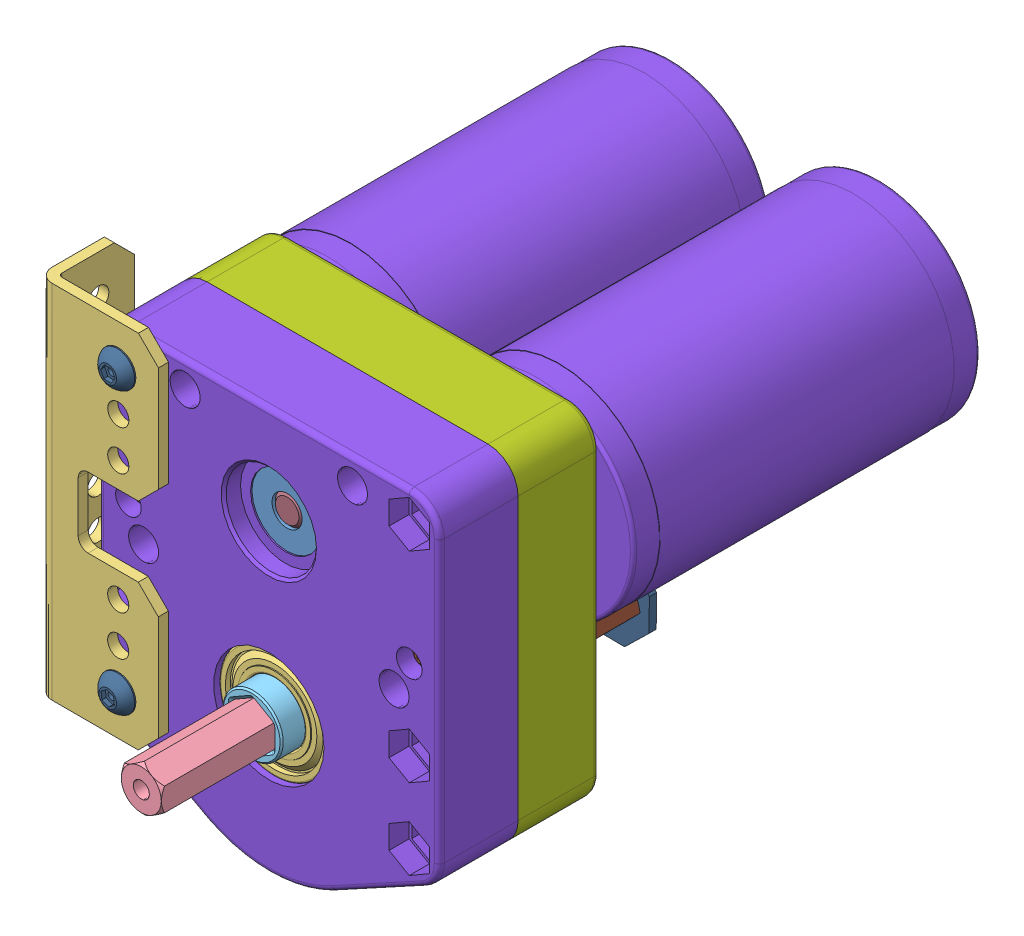
SolidWorks assembly 217-2428 LEFT, configuration Default. Lengths in mm.
Overall size (144.51 134.21 205.51).
82 component instances, 46 part files, 7 mates.
Components (placement in the parent):
- 217-2733-1: 217-2733 [Default] at (0 53.4162 12.0523) x (0 0 1) z (-0.971723 0.236125 0) size (7.11 24.61 24.61)
- 217-2733-2: 217-2733 [Default] at (0 53.4162 -17.6911) x (0 0 -1) z (0.971421 0.237365 0) size (7.11 24.61 24.61)
- 217-2731-1: 217-2731 [Default] at (0 0 -25.6286) x (1 0 0) z (0 -1 0) size (31.12 7.94 31.12)
- 217-2789-1: 217-2789 [Default] at (0 0 17.6784) x (0 0 -1) z (0.906537 -0.422126 0) size (11.1 38.4 38.4)
- 217-2778-001 Rev2_NCQ8A075-050M-1: 217-2778-001 Rev2_NCQ8A075-050M [Default] at (0 0 -79.4639) x (-0.681873 0.731471 0) z (0 0 1) size (31.75 33.34 41.8)
  - 217-2778-NCQ8A075-050M_NCQ8 Tube_075A-1: 217-2778-NCQ8A075-050M_NCQ8 Tube_075A [Default] at origin size (31.75 33.34 26.92)
  - 217-2778-NCQ8A075-050M_NCQ8 Rod_075M-1: 217-2778-NCQ8A075-050M_NCQ8 Rod_075M [Default] at (0 0 -6.927) x (-1 0 0) z (0 0 1) size (18.95 18.95 35.27)
  - 217-2778-NCQ8A075-050M_Snap Ring_075-1: 217-2778-NCQ8A075-050M_Snap Ring_075 [Default] at (0 0 10.362) size (21 20.74 0.97)
- 217-2428-027 Rev1_97414A630-1: 217-2428-027 Rev1_97414A630 [Default] at (0 0 -44.8925) x (0 0 1) z (0.453751 0.891129 0) size (0.64 5.89 7.9)
- 217-2788_57155K375-1: 217-2788_57155K375 [Default] at (0 0 -46.7975) x (0.971787 -0.235861 0) z (0 0 1) size (9.53 9.53 3.17)
- 217-2428-011 Rev2-1: 217-2428-011 Rev2 [Default] at (0 0 -53.992) x (0 -1 0) z (0 0 -1) size (18.03 18.03 17.56)
- 217-2428-012 Rev1-1: 217-2428-012 Rev1 [Default] at (-0.0022 -0.3376 -66.0019) x (0.999912 -0.013293 0) z (0 0 1) size (63.5 25.4 2.29)
- 217-2428-027 Rev1_97414A630-2: 217-2428-027 Rev1_97414A630 [Default] at (0 0 -48.7025) x (0 0 1) z (-0.054891 -0.998492 0) size (0.64 5.89 7.9)
- 217-2428-005 Rev1-1: 217-2428-005 Rev1 [Default] at (25.3955 -0.6753 -44.6659) x (-0.968533 0.248884 0) z (0.248884 0.968533 0) size (7.33 38.98 6.35)
- 217-2428-005 Rev1-2: 217-2428-005 Rev1 [Default] at (-25.4 0 -44.6659) x (0.661665 -0.7498 0) z (-0.7498 -0.661665 0) size (7.33 38.98 6.35)
- SCREW-B-440-0250_91306A311-1: SCREW-B-440-0250_91306A311 [Default] at (3.4925 6.0492 -45.21) x (0.999997 0.002364 0) z (0 0 1) size (5.45 5.47 5.03)
- SCREW-B-440-0250_91306A311-2: SCREW-B-440-0250_91306A311 [Default] at (3.4925 -6.0492 -45.21) x (0.883226 0.468948 0) z (0 0 1) size (5.45 5.47 5.03)
- SCREW-B-440-0250_91306A311-3: SCREW-B-440-0250_91306A311 [Default] at (-6.985 0 -45.21) size (5.45 5.47 5.03)
- SCREW-832-0375-1: SCREW-832-0375 [Default] at (25.3955 -0.6753 -68.2117) x (0 0 1) z (-0.875404 0.483392 0) size (11.73 7.92 7.92)
- SCREW-832-0375-2: SCREW-832-0375 [Default] at (-25.4 0 -68.2117) x (0 0 1) z (-0.875404 0.483392 0) size (11.73 7.92 7.92)
- SCREW-832-0375-3: SCREW-832-0375 [Default] at (25.3955 -0.6753 -20.2311) x (0 0 -1) z (1 0 0) size (11.73 7.92 7.92)
- SCREW-832-0375-4: SCREW-832-0375 [Default] at (-25.4 0 -20.2311) x (0 0 -1) z (0.999351 0.036025 0) size (11.73 7.92 7.92)
- SBS1_SBS-0632-0250-1: SBS1_SBS-0632-0250 [Default] at (15.4904 -0.5436 -61.8617) x (0 0 -1) z (0.854303 -0.519775 0) size (8.57 6.68 6.65)
- SBS1_SBS-0632-0250-2: SBS1_SBS-0632-0250 [Default] at (-15.4949 -0.1317 -61.8617) x (0 0 -1) z (0.854303 -0.519775 0) size (8.57 6.68 6.65)
- 217-2428-016 Rev2_Spur01-1: 217-2428-016 Rev2_Spur01 [Default] at (0 0 -29.2676) x (0.982225 0.187706 0) z (0 0 1) size (40.67 40.74 13.3)
- 217-2428-017 Rev2-1: 217-2428-017 Rev2 [Default] at (-12.7 -21.997 -29.2989) x (-0.40695 -0.913451 0) z (0 0 1) size (14.73 14.73 7.37)
- 217-2428-018 Rev2-1: 217-2428-018 Rev2 [Default] at (-12.7 -21.997 -39.9034) x (0.866025 -0.5 0) z (0 0 1) size (41.28 25.4 6.92)
- 217-2788_57155K375-2: 217-2788_57155K375 [Default] at (-12.7 -21.997 -34.5694) x (-0.775754 -0.631035 0) z (0 0 -1) size (9.53 9.53 3.17)
- 217-2788_57155K375-3: 217-2788_57155K375 [Default] at (-12.7 -21.997 -24.0284) x (0.47232 -0.881427 0) z (0 0 1) size (9.53 9.53 3.17)
- 217-2428-009 Rev1-1: 217-2428-009 Rev1 [Default] at (-3.6662 -34.925 -31.9659) x (-0.555959 0.831209 0) z (0.831209 0.555959 0) size (7.33 13.58 6.35)
- 217-2428-009 Rev1-2: 217-2428-009 Rev1 [Default] at (-28.4129 -20.6375 -31.9659) x (-0.555959 0.831209 0) z (0.831209 0.555959 0) size (7.33 13.58 6.35)
- SCREW-832-0250-1: SCREW-832-0250 [Default] at (-28.4129 -20.6375 -42.1132) x (0 0 1) z (-0.923728 -0.383049 0) size (8.56 7.92 7.92)
- SCREW-832-0375-5: SCREW-832-0375 [Default] at (-28.4129 -20.6375 -20.2311) x (0 0 -1) z (-0.274582 -0.961564 0) size (11.73 7.92 7.92)
- SCREW-832-0375-6: SCREW-832-0375 [Default] at (-3.6662 -34.925 -20.2311) x (0 0 -1) z (-0.826375 -0.56312 0) size (11.73 7.92 7.92)
- SCREW-832-0250-2: SCREW-832-0250 [Default] at (-3.6662 -34.925 -42.1132) x (0 0 1) z (-0.923728 -0.383049 0) size (8.56 7.92 7.92)
- PINL-0250-1125-S-1: PINL-0250-1125-S [Default] at (-12.7 -21.997 -35.3949) x (0 0 -1) z (0.874919 -0.48427 0) size (28.57 6.35 6.35)
- 217-2428-024 Rev2-1: 217-2428-024 Rev2 [Default] at (-69.8817 30.3756 12.8651) x (-0.000714 -1 0) z (1 -0.000714 0) size (114.3 27.31 38.1)
- SBS1_SBS1032-0500ZC-1: SBS1_SBS1032-0500ZC [Default] at (-39.6321 27.2942 -19.8755) x (0 0 -1) z (0.996655 0.081722 0) size (15.78 9.29 9.24)
- SBS1_SBS1032-0500ZC-2: SBS1_SBS1032-0500ZC [Default] at (-26.4841 76.3632 -19.8755) x (0 0 -1) z (0.751237 -0.660033 0) size (15.78 9.29 9.24)
- 217-2614-001_12t-1: 217-2614-001_12t [Default] at (-33.0581 51.8287 -4.1095) x (-0.965926 0.258819 0) z (0 0 1) size (18.29 18.29 19)
- 217-2761-001 rev1-1: 217-2761-001 rev1 [Default] at (-34.0416 48.1582 -9.5159) x (0.965926 -0.258819 0) z (0 0 1) size (2 2 20)
- SBS1_SBS1032-0500ZC-3: SBS1_SBS1032-0500ZC [Default] at (39.6321 27.2942 -19.8755) x (0 0 -1) z (0.618676 -0.785646 0) size (15.78 9.29 9.24)
- SBS1_SBS1032-0500ZC-4: SBS1_SBS1032-0500ZC [Default] at (26.4841 76.3632 -19.8755) x (0 0 -1) z (0.996655 0.081722 0) size (15.78 9.29 9.24)
- 217-2761-001 rev1-2: 217-2761-001 rev1 [Default] at (32.0746 55.4992 -9.5159) x (0.965926 0.258819 0) z (0 0 1) size (2 2 20)
- 217-2614-001_12t-2: 217-2614-001_12t [Default] at (33.0581 51.8287 -4.1095) x (0.965926 0.258819 0) z (0 0 1) size (18.29 18.29 19)
- 217-2428-001 Rev1-1: 217-2428-001 Rev1 [Default] at (0 53.4162 -25.6159) size (107.95 127.51 28.8)
- 217-2428-002 Rev1-1: 217-2428-002 Rev1 [Default] at (0 53.4162 24.9301) x (-1 0 0) z (0 0 -1) size (107.95 127.51 28.11)
- 217-2703-001-1: 217-2703-001 [Default] at (0 53.4162 4.5339) x (0.013293 -0.999912 0) z (0 0 1) size (33.29 33.29 12.65)
- 217-2707-001_40t-1: 217-2707-001_40t [Default] at (0 53.4162 -8.1661) x (-0.872595 0.488444 0) z (0 0 1) size (53.62 53.62 12.65)
- SBS1_SBS0832-1750SS-1: SBS1_SBS0832-1750SS [Default] at (-44.45 36.7075 21.4249) x (0 0 -1) z (0.052618 -0.998615 0) size (47.11 8.02 7.99)
- SBS1_SBS0832-1750SS-2: SBS1_SBS0832-1750SS [Default] at (44.45 36.7075 21.4249) x (0 0 -1) z (0.699378 -0.714752 0) size (47.11 8.02 7.99)
- Nylock Nut_NNY2520-ZC-1: Nylock Nut_NNY2520-ZC [Default] at (44.45 -14.0925 -17.7546) x (-0.164279 0.986414 0) z (0 0 -1) size (12.85 11.89 7.62)
- Nylock Nut_NNY2520-ZC-2: Nylock Nut_NNY2520-ZC [Default] at (44.45 74.8075 -17.7546) x (0 1 0) z (0 0 -1) size (12.85 11.89 7.62)
- 217-2428-004 Rev3-1: 217-2428-004 Rev3 [Default] at (0 53.4162 -2.8448) x (-0.511468 0.859302 0) z (0 0 1) size (11 9.53 43.92)
- 217-2428-021 Rev1-1: 217-2428-021 Rev1 [Default] at (0 53.4162 -16.1036) x (0.426322 -0.904572 0) z (0 0 1) size (15.88 15.88 3.17)
- 217-2428-029 Rev1-1: 217-2428-029 Rev1 [Default] at (0 53.4162 11.4173) size (15.88 15.88 1.12)
- Nylock 8-32-1: Nylock 8-32 [Default] at (44.45 36.7075 -19.2659) x (0.254216 0.967147 0) z (-0.967147 0.254216 0) size (10.2 4.9 8.12)
- Nylock 8-32-2: Nylock 8-32 [Default] at (-44.45 36.7075 -19.2659) x (0.948441 0.316954 0) z (-0.316954 0.948441 0) size (10.2 4.9 8.12)
- 217-2792-001 Rev1-1: 217-2792-001 Rev1 [Default] at (0 0 -25.5778) x (0 1 0) z (0 0 1) size (82.92 82.92 116)
  - 217-2428-008 Rev1-1: 217-2428-008 Rev1 [Default] at (0 0 10.2679) size (31.75 31.75 1.59)
  - 217-2428-028 Rev1_97633A250-1: 217-2428-028 Rev1_97633A250 [Default] at (0 0 37.1221) x (0 0 1) z (0.9357 -0.352797 0) size (1.07 23.39 21.18)
  - 217-2709-101 Rev1-1: 217-2709-101 Rev1 [Default] at (0 0 20.7137) x (0.993517 0.113685 0) z (0 0 -1) size (62.31 62.31 12.7)
    - 217-2428-022 Rev1-1: 217-2428-022 Rev1 [Default] at origin size (28.57 28.57 6.1)
    - 217-2709-001_44t Steel-1: 217-2709-001_44t Steel [Default] at (0 0 3.302) x (0.062728 -0.998031 0) z (0 0 1) size (58.74 58.74 11.11)
  - 217-2713-101 Rev1-1: 217-2713-101 Rev1 [Default] at (0 0 33.4137) x (-0.01285 0.999917 0) z (0 0 -1) size (81.88 81.88 12.7)
    - 217-2713-001_60t Steel-1: 217-2713-001_60t Steel [Default] at (0 0 3.302) x (0.999266 -0.038302 0) z (0 0 1) size (78.91 78.91 11.11)
    - 217-2428-022 Rev1-1: 217-2428-022 Rev1 [Default] at origin size (28.57 28.57 6.1)
  - 217-2790-001 Rev1-1: 217-2790-001 Rev1 [Default] x (-1 0 0) z (0 0 1) size (22.23 22.23 116)
    - 217-2790-002 Rev1-1: 217-2790-002 Rev1 [Default] at (0 0 62.9285) x (0 0 1) z (1 0 0) size (55.88 12.7 16.13)
    - 217-2790-003 Rev1-1: 217-2790-003 Rev1 [Default] at origin size (22.23 22.23 55.94)
    - 217-2790-004 Rev1-1: 217-2790-004 Rev1 [Default] at (0 0 14.3911) x (0.928141 0.372229 0) z (0 0 1) size (11.68 11.68 44.12)
  - 217-2428-007 Rev1-1: 217-2428-007 Rev1 [Default] at (6.3246 0 14.2494) x (0.485433 0.3648 -0.794529) z (-0.690104 -0.398066 -0.6044) size (6.35 6.35 6.35)
  - 217-2428-007 Rev1-2: 217-2428-007 Rev1 [Default] at (9.017 0 26.9494) x (0.741485 -0.614816 -0.268704) z (-0.150074 0.23836 -0.959512) size (6.35 6.35 6.35)
  - 217-2428-007 Rev1-3: 217-2428-007 Rev1 [Default] at (-3.1623 5.4773 14.2494) x (-0.558642 0.237997 -0.794529) z (0.689788 -0.398615 -0.6044) size (6.35 6.35 6.35)
  - 217-2428-007 Rev1-4: 217-2428-007 Rev1 [Default] at (-3.1623 -5.4773 14.2494) x (0.073209 -0.602797 -0.794529) z (0.000317 0.796681 -0.6044) size (6.35 6.35 6.35)
  - 217-2428-007 Rev1-5: 217-2428-007 Rev1 [Default] at (-4.5085 7.809 26.9494) x (0.161703 0.949553 -0.268704) z (-0.131389 -0.249147 -0.959512) size (6.35 6.35 6.35)
  - 217-2428-007 Rev1-6: 217-2428-007 Rev1 [Default] at (-4.5085 -7.809 26.9494) x (-0.903188 -0.334737 -0.268704) z (0.281462 0.010788 -0.959512) size (6.35 6.35 6.35)
- 217-2000-1: 217-2000 [Default] at (33.0581 51.8287 -25.6159) x (0 0 -1) z (0.965926 0.258819 0) size (150.2 64.01 64.01)
- 217-2000-2: 217-2000 [Default] at (-33.0581 51.8287 -25.6159) x (0 0 -1) z (-0.965926 0.258819 0) size (150.2 64.01 64.01)
- E4P-X-250-X-D-D-D-X-1: E4P-X-250-X-D-D-D-X [Default] at (-12.7 -21.997 -39.9034) x (0.5 0.866025 0) z (-0.866025 0.5 0) size (24.87 14.38 22.9)
- SBS1_SBS2520-2000ZC-2: SBS1_SBS2520-2000ZC [Default] at (-44.45 -14.0925 31.4579) x (0 0 -1) z (0.393526 0.919313 0) size (54.83 11.22 11.17)
- SBS1_SBS2520-2000ZC-3: SBS1_SBS2520-2000ZC [Default] at (-44.45 74.8075 31.4579) x (0 0 -1) z (-0.895741 -0.444577 0) size (54.83 11.22 11.17)
Mates (geometry in assembly coordinates):
- Tangent1: tangent aligned: cylinder of 217-2428-024 Rev2-1 through (-44.5135 -14.0925 28.1051) axis (0 0 -1) radius 3.3655; cylinder of 217-2428-002 Rev1-1 through (-44.45 -14.0925 10.9601) axis (0 0 1) radius 3.302
- Concentric2: concentric anti-aligned: cylinder of 217-2428-024 Rev2-1 through (-44.45 74.8075 28.1051) axis (0 0 -1) radius 3.3655; cylinder of 217-2428-002 Rev1-1 through (-44.45 74.8075 10.9601) axis (0 0 1) radius 3.302
- Coincident1: coincident anti-aligned: plane of 217-2428-024 Rev2-1 through (-31.7409 87.4984 24.9301) normal (0 0 -1); plane of 217-2428-002 Rev1-1 through (-44.45 74.8075 24.9301) normal (0 0 1)
- Concentric3: concentric anti-aligned: cylinder of 217-2428-002 Rev1-1 through (-44.45 -14.0925 10.9601) axis (0 0 1) radius 3.302; circle of SBS1_SBS2520-2000ZC-2
- Coincident2: coincident anti-aligned: plane of 217-2428-024 Rev2-1 through (-31.7409 87.4984 28.1051) normal (0 0 1); plane of SBS1_SBS2520-2000ZC-2 through (-47.3688 -12.8431 28.1051) normal (0 0 -1)
- Concentric4: concentric anti-aligned: cylinder of 217-2428-024 Rev2-1 through (-44.45 74.8075 28.1051) axis (0 0 -1) radius 3.3655; cylinder of SBS1_SBS2520-2000ZC-3 through (-44.45 74.8075 31.4579) axis (0 0 1) radius 3.175
- Coincident3: coincident anti-aligned: plane of 217-2428-024 Rev2-1 through (-31.7409 87.4984 28.1051) normal (0 0 1); plane of SBS1_SBS2520-2000ZC-3 through (-43.0385 71.9635 28.1051) normal (0 0 -1)
